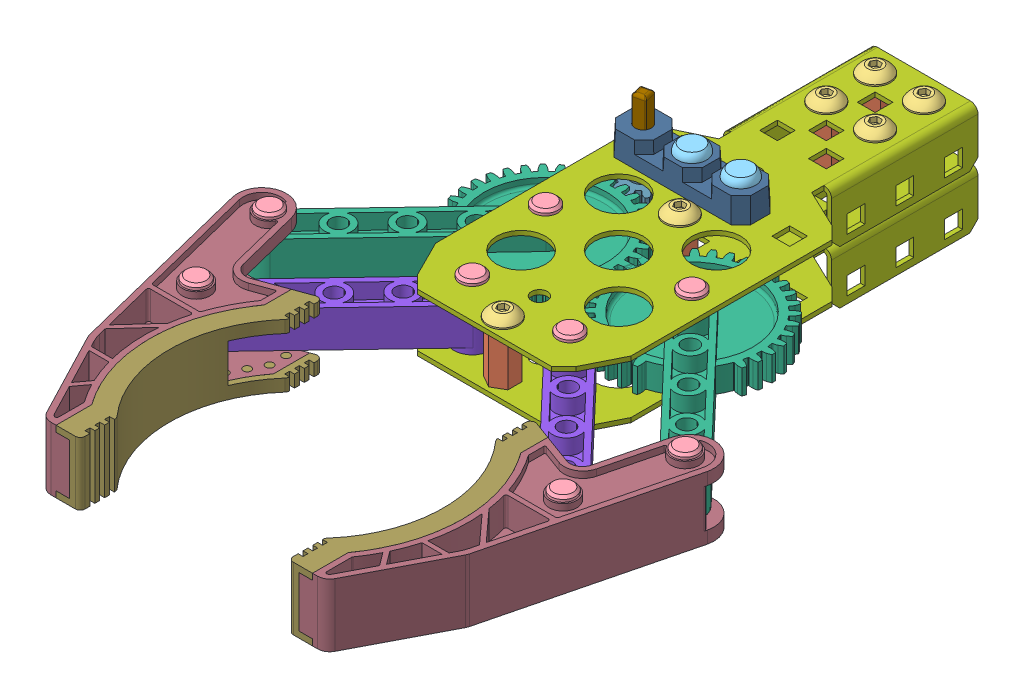
SolidWorks assembly Vex-Claw-Assy, configuration Default. Lengths in mm.
Overall size (143.62 50.81 192.38).
42 component instances, 14 part files, 0 mates.
Components (placement in the parent):
- WASHER-TEFLON-1: WASHER-TEFLON [Default] at (-19.05 12.954 -3.175) size (10.16 0.91 10.16)
- BEAM-0500-1: BEAM-0500 [Default] at (-6.35 13.8684 -50.8) x (1 0 0) z (0 -1 0) size (6.35 7.33 12.7)
- SCREW-832_SBS0832-0250ZB-1: SCREW-832_SBS0832-0250ZB [Default] at (0 -2.2098 52.3875) x (0 1 0) z (0 0 1) size (8.56 7.92 7.92)
- Vex-Claw-Pin-1: Vex-Claw-Pin [Default] at (19.05 -1.0541 22.225) size (6.35 19.3 6.35)
- BEARING-RIVET-1: BEARING-RIVET [Default] at (-6.35 21.3868 -3.175) size (7.62 13.34 7.62)
- Vex-Claw-Pin-2: Vex-Claw-Pin [Default] at (-12.7 -1.0541 47.625) size (6.35 19.3 6.35)
- SCREW-832_SBS0832-0250ZB-2: SCREW-832_SBS0832-0250ZB [Default] at (-6.35 17.2466 -38.1) x (0 -1 0) z (0 0 1) size (8.56 7.92 7.92)
- Vex-Claw-Pin-3: Vex-Claw-Pin [Default] at (47.7198 -1.0541 84.4252) size (6.35 19.3 6.35)
- SCREW-832_SBS0832-0250ZB-3: SCREW-832_SBS0832-0250ZB [Default] at (0 17.2466 6.35) x (0 -1 0) z (0 0 1) size (8.56 7.92 7.92)
- SCREW-832_SBS0832-0250ZB-4: SCREW-832_SBS0832-0250ZB [Default] at (0 17.2466 52.3875) x (0 -1 0) z (0 0 1) size (8.56 7.92 7.92)
- Vex-CLAW-GEAR-LINKAGE-1: Vex-CLAW-GEAR-LINKAGE [Default] at (19.05 4.3434 22.225) x (0.757452 0 -0.652891) z (0 -1 0) size (40.2 75.6 12.7)
- Vex-Claw-Pin-4: Vex-Claw-Pin [Default] at (-47.7198 -1.0541 84.4252) size (6.35 19.3 6.35)
- Vex-Claw-Pin-5: Vex-Claw-Pin [Default] at (-54.0698 -1.0541 59.0252) size (6.35 19.3 6.35)
- BEAM-0500-2: BEAM-0500 [Default] at (6.35 13.8684 -50.8) x (1 0 0) z (0 -1 0) size (6.35 7.33 12.7)
- Vex-Claw-Pin-6: Vex-Claw-Pin [Default] at (12.7 -1.0541 47.625) size (6.35 19.3 6.35)
- BEAM-0500-3: BEAM-0500 [Default] at (-6.35 13.8684 -38.1) x (1 0 0) z (0 -1 0) size (6.35 7.33 12.7)
- BEAM-0500-4: BEAM-0500 [Default] at (0 1.1684 52.3875) x (1 0 0) z (0 1 0) size (6.35 7.33 12.7)
- Vex-Claw-Brk RevA-1: Vex-Claw-Brk RevA [Default] at (0 13.8684 0) size (50.8 13.87 114.3)
- Vex-Claw-Pin-7: Vex-Claw-Pin [Default] at (-19.05 -1.0541 22.225) size (6.35 19.3 6.35)
- Vex-Claw-Pin-8: Vex-Claw-Pin [Default] at (54.0698 -1.0541 59.0252) size (6.35 19.3 6.35)
- Vex-CLAW-LINKAGE-1: Vex-CLAW-LINKAGE [Default] at (-12.7 7.5184 47.625) x (0.689366 0 -0.724413) z (0.724413 0 0.689366) size (60.33 12.7 9.53)
- SHAFT-2000-1: SHAFT-2000 [Default] at (-19.05 3.27 -3.175) x (0.222378 0 0.974961) z (0 -1 0) size (3.18 3.18 50.81)
- BEARING-FLAT-1: BEARING-FLAT [Default] at (-32.766 104.013 9.525) x (0 -1 0) z (0 0 1) size (7.04 35.56 10.16)
- SCREW-832_SBS0832-0250ZB-5: SCREW-832_SBS0832-0250ZB [Default] at (6.35 17.2466 -38.1) x (0 -1 0) z (0 0 1) size (8.56 7.92 7.92)
- SCREW-832_SBS0832-0250ZB-6: SCREW-832_SBS0832-0250ZB [Default] at (0 -2.2098 6.35) x (0 1 0) z (0 0 1) size (8.56 7.92 7.92)
- Vex-CLAW-LINKAGE-2: Vex-CLAW-LINKAGE [Default] at (12.7 7.5184 47.625) x (-0.689366 0 -0.724413) z (0.724413 0 -0.689366) size (60.33 12.7 9.53)
- SCREW-832_SBS0832-0250ZB-7: SCREW-832_SBS0832-0250ZB [Default] at (-6.35 17.2466 -50.8) x (0 -1 0) z (0 0 1) size (8.56 7.92 7.92)
- Vex-CLAW-GEAR-LINKAGE-2: Vex-CLAW-GEAR-LINKAGE [Default] at (-19.05 4.3434 22.225) x (0.68962 0 0.724171) z (0 -1 0) size (40.2 75.6 12.7)
- BEAM-0500-5: BEAM-0500 [Default] at (0 1.1684 6.35) x (0.640872 0 -0.767648) z (0 1 0) size (6.35 7.33 12.7)
- BEARING-RIVET-2: BEARING-RIVET [Default] at (6.35 22.0312 -3.175) size (7.62 13.34 7.62)
- SHAFT-COLLAR-1: SHAFT-COLLAR [Default] at (-19.05 -6.3881 -3.175) size (11 6.39 11)
- BEAM-0500-6: BEAM-0500 [Default] at (6.35 13.8684 -38.1) x (1 0 0) z (0 -1 0) size (6.35 7.33 12.7)
- WASHER-TEFLON-2: WASHER-TEFLON [Default] at (-19.05 1.1684 -3.175) size (10.16 0.91 10.16)
- Vex-CLAW-FINGER-ASSY-1: Vex-CLAW-FINGER-ASSY [Default] at (-47.7198 15.4559 84.4252) x (1 0 0) z (0 0 -1) size (34.89 16.39 82.17)
  - Vex-CLAW-FINGER-RUBBER-1: Vex-CLAW-FINGER-RUBBER [Default] at origin size (13.6 16.38 62.95)
  - Vex-CLAW-FINGER-1: Vex-CLAW-FINGER [Default] at origin size (32.12 16.39 82.17)
- Vex-Claw-Brk RevA-2: Vex-Claw-Brk RevA [Default] at origin size (50.8 13.87 114.3)
- SCREW-832_SBS0832-0250ZB-8: SCREW-832_SBS0832-0250ZB [Default] at (6.35 17.2466 -50.8) x (0 -1 0) z (0 0 1) size (8.56 7.92 7.92)
- Vex-CLAW-FINGER-ASSY-2: Vex-CLAW-FINGER-ASSY [Default] at (47.7198 -0.9271 84.4252) x (-1 0 0) z (0 0 -1) size (34.89 16.39 82.17)
  - Vex-CLAW-FINGER-RUBBER-1: Vex-CLAW-FINGER-RUBBER [Default] at origin size (13.6 16.38 62.95)
  - Vex-CLAW-FINGER-1: Vex-CLAW-FINGER [Default] at origin size (32.12 16.39 82.17)
- VEX-12-TOOTH-GEAR-1: VEX-12-TOOTH-GEAR [Default] at (-19.05 3.4798 -3.175) x (0.222378 0 0.974961) z (0 -1 0) size (14.77 14.77 9.14)
